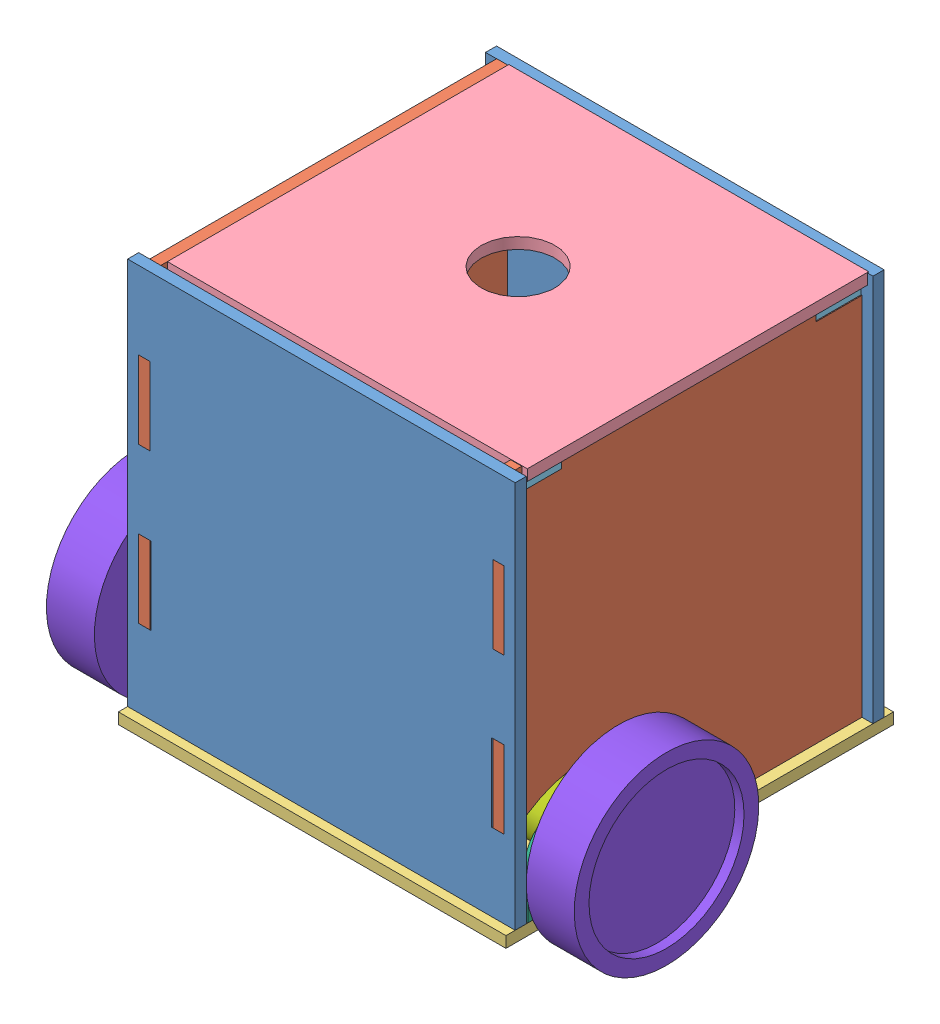
SolidWorks assembly Rubiks_cube_assem, configuration Default. Lengths in mm.
Overall size (286 249.76 230.98).
16 component instances, 8 part files, 24 mates.
Components (placement in the parent):
- side back and front-1: side back and front [Default] at (-31.7093 67.9469 -11) x (-1 0 0) z (0 1 0) size (210 6 216)
- side squared-1: side squared [Default] at (50.8748 124.9286 -94.2857) x (0 0 1) z (0 -1 0) size (200 6 216)
- square base-1: square base [Default] at (-47.2743 0 -109.3835) size (210 6 210)
- top-1: top [Default] at (-34.1044 210.1559 -219.0747) x (0 0 -1) z (0.999999 0.001457 0) size (185 6 195)
- top holder-1: top holder [Default] at (-115.6035 204 21.0652) x (0 0 1) z (-1 0 0) size (24.5 6 198)
- top holder-2: top holder [Default] at (19.353 204.5004 -231.0652) x (0 0 -1) z (1 0 0) size (24.5 6 198)
- side squared-2: side squared [Default] at (-141.1252 124.9286 -94.2857) x (0 0 1) z (0 -1 0) size (200 6 216)
- side back and front-2: side back and front [Default] at (-31.7093 67.9469 -204.9084) x (-1 0 0) z (0 1 0) size (210 6 216)
- wheel_assy-1: wheel_assy [Default] at (-179.234 2.6183 8.7256) x (0 1 0) z (0 0 -1) size (139.95 113 139.95)
  - bracket-1: bracket [Default] at (33.8817 26.1088 57.7256) size (45 25 74)
  - emd30-1: emd30 [Default] at (26.622 101.1088 57.6925) x (-0.00456 0 0.99999) z (0.99999 0 0.00456) size (30 77 30)
  - wheel_to_check_hub_dimensions-1: wheel_to_check_hub_dimensions [Default] at (33.8817 14.1088 57.7256) x (0.598067 0 -0.801446) z (-0.801446 0 -0.598067) size (100 36 100)
- wheel_assy-2: wheel_assy [Default] at (82.9835 2.6183 -106.7256) x (0 1 0) z (0 0 1) size (139.95 113 139.95)
  - bracket-1: bracket [Default] at (33.8817 26.1088 57.7256) size (45 25 74)
  - emd30-1: emd30 [Default] at (26.622 101.1088 57.6925) x (-0.00456 0 0.99999) z (0.99999 0 0.00456) size (30 77 30)
  - wheel_to_check_hub_dimensions-1: wheel_to_check_hub_dimensions [Default] at (33.8817 14.1088 57.7256) x (0.598067 0 -0.801446) z (-0.801446 0 -0.598067) size (100 36 100)
Mates (geometry in assembly coordinates):
- Coincident6: coincident: line of side squared-1 through (44.8748 0 -162) axis (1 0 0); line of square base-1 through (44.3026 0 -162) axis (1 0 0)
- Coincident7: coincident: line of side squared-1 through (44.8748 0 -138) axis (0 0 1); line of square base-1 through (44.8748 0 -138) axis (0 0 1)
- Coincident12: coincident: plane of side squared-1 through (44.8748 210 -36) normal (0 0 1); plane of top holder-1 through (50.8748 210 -36) normal (0 0 -1)
- Coincident13: coincident: line of side squared-1 through (50.8748 204 -36) axis (0 1 0); line of top holder-1 through (50.8748 210 -36) axis (0 -1 0)
- Coincident15: coincident: plane of square base-1 through (-47.2743 0 -109.3835) normal (0 -1 0); plane of side squared-2 through (-147.1252 0 -162) normal (0 -1 0)
- Coincident16: coincident: plane of square base-1 through (-147.1252 6 -186) normal (0 0 1); plane of side squared-2 through (-147.1252 0 -186) normal (0 0 -1)
- Coincident17: coincident: plane of square base-1 through (-141.1252 6 -138) normal (-1 0 0); plane of side squared-2 through (-141.1252 6 -49) normal (1 0 0)
- Coincident18: coincident: plane of top holder-1 through (-115.6035 210 21.0652) normal (0 1 0); plane of side squared-2 through (-147.1252 210 -11) normal (0 -1 0)
- Coincident20: coincident: plane of square base-1 through (-47.2743 0 -109.3835) normal (0 -1 0); plane of assembly through (0 0 0) normal (0 1 0)
- Coincident21: coincident: plane of square base-1 through (-153.1252 6 0) normal (0 0 1); plane of assembly through (0 0 0) normal (0 0 1)
- Coincident22: coincident: line of side squared-1 through (50.8748 210 -174) axis (0 -1 0); line of top holder-2 through (50.8748 210.5004 -174) axis (0 -1 0)
- Coincident27: coincident: line of square base-1 through (-147.1252 6 -205) axis (0 0 1); line of side back and front-2 through (-147.1252 6 -198.9084) axis (0 0 -1)
- Coincident28: coincident: line of square base-1 through (50.8748 0 -199) axis (0 0 -1); line of side back and front-2 through (50.8748 0 -198.9084) axis (0 0 -1)
- Coincident35: coincident: line of top-1 through (-141.1252 216 -199.5625) axis (0 0 1); line of side squared-2 through (-141.1252 216 -11) axis (0 0 -1)
- Parallel4: parallel: line of side squared-1 through (44.8748 216 -11) axis (0 0 -1); line of top-1 through (53.8746 216.2841 -14.5625) axis (0 0 -1)
- Coincident38: coincident: line of side back and front-1 through (-147.1252 6 -5) axis (0 0 -1); line of square base-1 through (-147.1252 6 -11) axis (0 0 1)
- Coincident39: coincident: plane of side back and front-1 through (-31.7093 67.9469 -11) normal (0 0 -1); plane of square base-1 through (-147.1252 6 -11) normal (0 0 1)
- Coincident40: coincident: line of side back and front-1 through (50.8748 6 -5) axis (0 0 -1); line of square base-1 through (50.8748 6 -5) axis (0 0 -1)
- Coincident41: coincident: plane of square base-1 through (-47.2743 6 -109.3835) normal (0 1 0); plane of wheel_assy-1/bracket-1 through (-151.1252 6 -12) normal (0 -1 0)
- Coincident42: coincident: circle of square base-1; circle of wheel_assy-1/bracket-1
- Coincident43: coincident: circle of square base-1; circle of wheel_assy-1/bracket-1
- Coincident44: coincident: plane of square base-1 through (-47.2743 6 -109.3835) normal (0 1 0); plane of wheel_assy-2/bracket-1 through (54.8748 6 -86) normal (0 -1 0)
- Coincident45: coincident: circle of square base-1; circle of wheel_assy-2/bracket-1
- Coincident46: coincident: circle of square base-1; circle of wheel_assy-2/bracket-1
